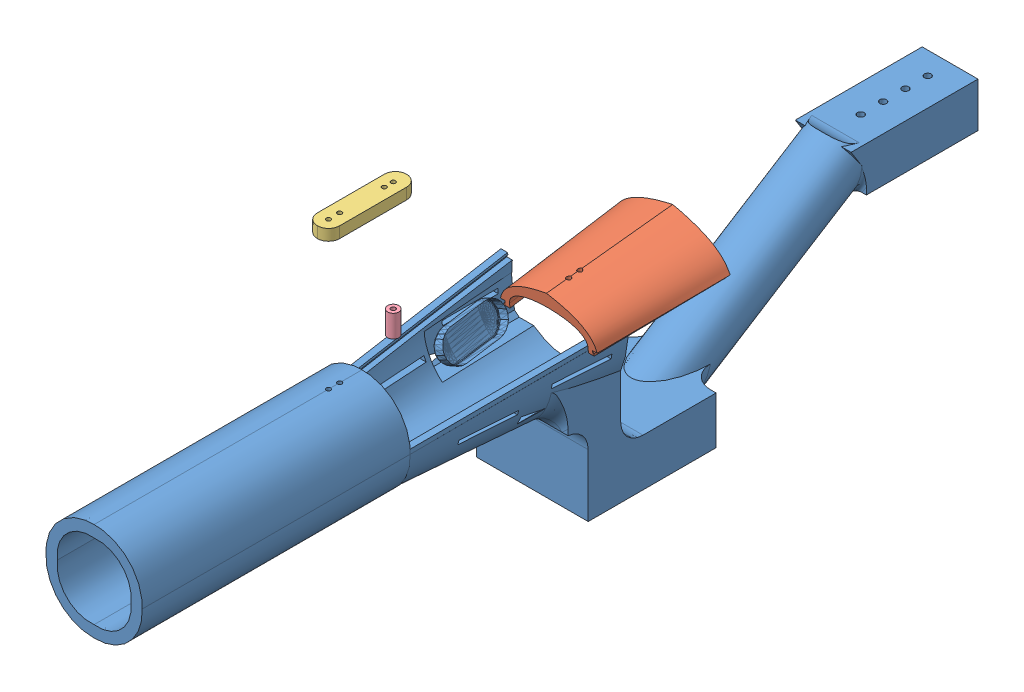
SolidWorks assembly Complete_Assembly, configuration Default. Lengths in mm.
Overall size (82.98 150.4 383.4).
4 component instances, 4 part files, 3 mates.
Components (placement in the parent):
- ExtendedHandleBase_circularHandle-1: ExtendedHandleBase_circularHandle [Default] at origin size (117.43 88.58 383.4)
- Vive Controller 1.5_handle1_MaleCoverUpside-2: Vive Controller 1.5_handle1_MaleCoverUpside [Default] at (25.9605 24.1818 -56.8175) x (0.999983 0 -0.005853) z (0.005853 0 0.999983) size (117.43 85.47 200.38)
- Attachment-1: Attachment [Default] at (0 73.5474 153.4031) x (0 0 1) z (-1 0 0) size (40 5 10)
- Spacer-1: Spacer [Default] at (0 19.3564 139.4031) x (0.938266 0 -0.345913) z (0.345913 0 0.938266) size (5 10 5)
Mates (geometry in assembly coordinates):
- Coincident6: coincident anti-aligned: cylinder of ExtendedHandleBase_circularHandle-1 through (0 12.6647 163.4031) axis (0 -1 0) radius 1; circle of Attachment-1
- Coincident7: coincident anti-aligned: cylinder of ExtendedHandleBase_circularHandle-1 through (0 12.6647 168.4031) axis (0 -1 0) radius 1; circle of Attachment-1
- Concentric2: concentric aligned: cylinder of Attachment-1 through (0 78.5474 139.4031) axis (0 -1 0) radius 1; cylinder of Spacer-1 through (0 29.3564 139.4031) axis (0 -1 0) radius 1
